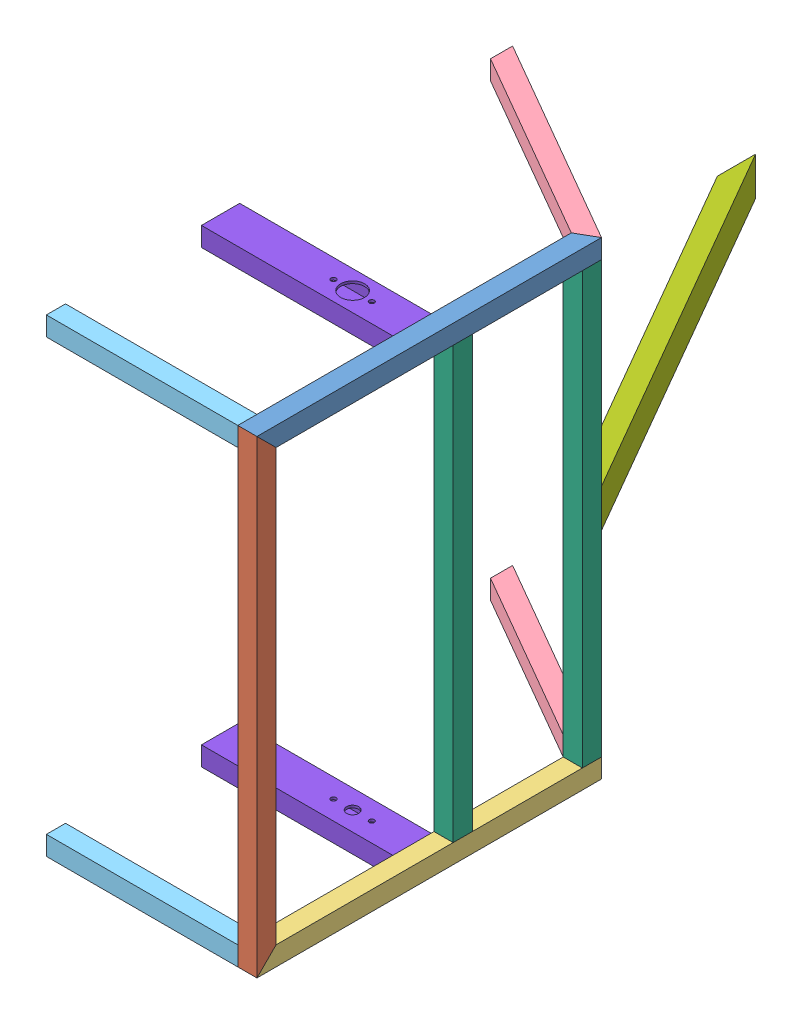
SolidWorks assembly chassis weldment bottom-1, configuration Default. Lengths in mm.
Overall size (301.4 622.3 941.13).
12 component instances, 8 part files, 0 mates.
Components (placement in the parent):
- bottom frame member side-1-1: bottom frame member side-1 [Default] at origin size (25.4 25.4 457.2)
- bottom frame member crossbrace-1-1: bottom frame member crossbrace-1 [Default] at (0 -298.45 215.9) x (0 0 -1) z (0 1 0) size (25.4 25.4 622.3)
- bottom frame member side_MIR-1-1: bottom frame member side_MIR-1 [Default] at (0 -596.9 0) x (1 0 0) z (0 0 -1) size (25.4 25.4 457.2)
- bottom frame member angle-1-1: bottom frame member angle-1 [Default] at (-133.1938 -596.9 -298.1671) x (0.5 0 -0.866025) z (0.866025 0 0.5) size (25.4 25.4 322.26)
- bottom frame member angle-1-2: bottom frame member angle-1 [Default] at (-133.1938 0 -298.1671) x (0.5 0 -0.866025) z (0.866025 0 0.5) size (25.4 25.4 322.26)
- bottom frame member back upright-1-1: bottom frame member back upright-1 [Default] at (-139.7 -596.9 215.9) x (0 0 -1) z (1 0 0) size (25.4 25.4 254)
- bottom frame member back upright-1-2: bottom frame member back upright-1 [Default] at (-139.7 0 215.9) x (0 0 -1) z (1 0 0) size (25.4 25.4 254)
- bottom frame member crossbrace back-1-1: bottom frame member crossbrace back-1 [Default] at (0 -298.45 -215.9) x (1 0 0) z (0 -1 0) size (25.4 25.4 571.5)
- bottom frame member brace-1-1: bottom frame member brace-1 [Default] at (-137.9985 -298.45 -464.2175) x (0 1 0) z (0.5 0 0.866025) size (50.8 25.4 558.8)
- bottom frame member crossbrace back-1-2: bottom frame member crossbrace back-1 [Default] at (0 -298.45 -44.45) x (1 0 0) z (0 1 0) size (25.4 25.4 571.5)
- wheel mount vertical-1-1: wheel mount vertical-1 [Default] at (-139.7 -596.9 -2.54) x (0 0 1) z (1 0 0) size (50.8 25.4 254)
- wheel mount vertical-1-2: wheel mount vertical-1 [Default] at (-139.7 0 -2.54) x (0 0 -1) z (1 0 0) size (50.8 25.4 254)
